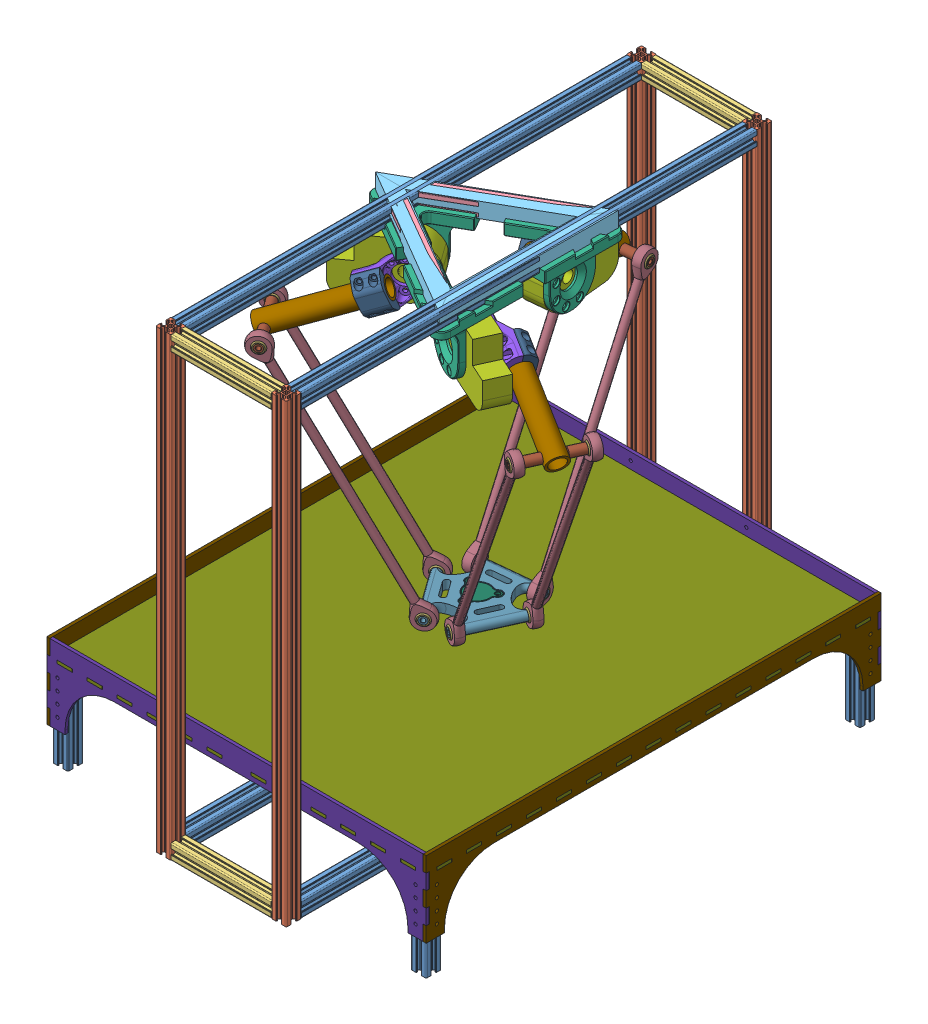
SolidWorks assembly delta-attached-dynamic-with-workspace, configuration Default. Lengths in mm.
Overall size (500 600 640).
80 component instances, 19 part files, 4 mates.
Components (placement in the parent):
- frame-1: frame [Default] at origin size (172.23 600 640)
  - alu-frame-length-1: alu-frame-length [End Finishing_Non-Machined End Finish Options_Type_Single_] at origin size (20 20 600)
  - alu-frame-height-1: alu-frame-height [End Finishing_Non-Machined End Finish Options_Type_Single_] at (0 -10 610) x (1 0 0) z (0 1 0) size (20 20 600)
  - alu-frame-height-2: alu-frame-height [End Finishing_Non-Machined End Finish Options_Type_Single_] at (0 -10 -10) x (1 0 0) z (0 1 0) size (20 20 600)
  - alu-frame-length-2: alu-frame-length [End Finishing_Non-Machined End Finish Options_Type_Single_] at (0 580 0) size (20 20 600)
  - alu-frame-width-1: alu-frame-width [End Finishing_Non-Machined End Finish Options_Type_Single_] at (10 0 610) x (0 0 -1) z (1 0 0) size (20 20 132.23)
  - alu-frame-width-2: alu-frame-width [End Finishing_Non-Machined End Finish Options_Type_Single_] at (10 0 -10) x (0 0 -1) z (1 0 0) size (20 20 132.23)
  - alu-frame-width-3: alu-frame-width [End Finishing_Non-Machined End Finish Options_Type_Single_] at (10 580 -10) x (0 0 -1) z (1 0 0) size (20 20 132.23)
  - alu-frame-width-4: alu-frame-width [End Finishing_Non-Machined End Finish Options_Type_Single_] at (10 580 610) x (0 0 -1) z (1 0 0) size (20 20 132.23)
  - alu-frame-height-3: alu-frame-height [End Finishing_Non-Machined End Finish Options_Type_Single_] at (152.23 -10 610) x (1 0 0) z (0 1 0) size (20 20 600)
  - alu-frame-height-4: alu-frame-height [End Finishing_Non-Machined End Finish Options_Type_Single_] at (152.23 -10 -10) x (1 0 0) z (0 1 0) size (20 20 600)
  - alu-frame-length-3: alu-frame-length [End Finishing_Non-Machined End Finish Options_Type_Single_] at (152.23 0 0) size (20 20 600)
  - alu-frame-length-4: alu-frame-length [End Finishing_Non-Machined End Finish Options_Type_Single_] at (152.23 580 0) size (20 20 600)
  - alu-frame-cross-strut-1: alu-frame-cross-strut [End Finishing_Non-Machined End Finish Options_Type_Single_] at (-10.4902 580 293.863) x (-0.5 0 -0.866025) z (0.866025 0 -0.5) size (20 20 164.23)
  - alu-frame-cross-strut-2: alu-frame-cross-strut [End Finishing_Non-Machined End Finish Options_Type_Single_] at (-10.4902 580 306.137) x (-0.5 0 0.866025) z (0.866025 0 0.5) size (20 20 164.23)
- delta-unattached-dynamic-1: delta-unattached-dynamic [Default] at (152.1394 570 300.5078) x (-0.006412 0 0.999979) z (-0.999979 0 -0.006412) size (388.36 442.87 421.7) (flexible)
  - base-1: base [Default] at origin size (276.1 104 273.55)
    - base^base-1: base^base [Default] at origin size (276.1 104 273.55) (virtual)
      - frame-triangle-1: frame-triangle [Default] at origin size (234.8 20 213.34)
        - frame-strut-triangle-1: frame-strut-triangle [Default] at origin size (234.8 20 20)
        - frame-strut-triangle-2: frame-strut-triangle [Default] at (50.04 0 86.6718) x (-0.5 0 0.866025) z (-0.866025 0 -0.5) size (234.8 20 20)
        - frame-strut-triangle-3: frame-strut-triangle [Default] at (-50.04 0 86.6718) x (-0.5 0 -0.866025) z (0.866025 0 -0.5) size (234.8 20 20)
      - base-mount-1: base-mount [Default] at (0 -47.5 143.3436) x (0.589337 0 0.807887) z (0 -1 0) size (108.14 103.78 86.5)
      - base-mount-2: base-mount [Default] at (74.0992 -47.5 15) x (0.404982 0 -0.914325) z (0 -1 0) size (108.14 103.78 86.5)
      - base-mount-3: base-mount [Default] at (-74.0992 -47.5 15) x (-0.994319 0 0.106438) z (0 -1 0) size (108.14 103.78 86.5)
      - Hebi-X5-1_draft-1: Hebi-X5-1_draft [Default] at (-95.9743 -47.5 17.3416) x (0 -1 0) z (-0.994319 0 0.106438) size (73 31.1 110)
      - Hebi-X5-1_draft-2: Hebi-X5-1_draft [Default] at (83.0088 -47.5 -5.1151) x (0 -1 0) z (0.404982 0 -0.914325) size (73 31.1 110)
      - Hebi-X5-1_draft-3: Hebi-X5-1_draft [Default] at (12.9654 -47.5 161.1172) x (0 -1 0) z (0.589337 0 0.807887) size (73 31.1 110)
  - proximal-link-1: proximal-link [Default] at (25.0038 -49.8947 147.2575) x (0.540088 -0.400189 0.740374) z (0.235846 0.916433 0.323308) size (174 92.2 48.61)
    - Proximal link^proximal-link-2: Proximal link^proximal-link [Default] at origin size (174 92.2 48.61) (virtual)
      - revolute-joint-1: revolute-joint [Default] at (-15.5275 13.2063 -4.1675) size (66.5 20.7 48.61)
      - proximal-link-1: proximal-link [Default] at (-3.0275 33.2063 -4.1675) x (0 0 -1) z (1 0 0) size (26 26 137.5)
      - joint-clamp-1: joint-clamp [Default] at (-3.0275 41.7563 -4.155) x (0 0 -1) z (1 0 0) size (48 17.3 30)
      - connection-tap-joint-1: connection-tap-joint [Default] at (124.4725 79.1063 -4.1675) x (0.500772 0 0.865579) z (0.865579 0 -0.500772) size (12 32.9 12)
      - connection-tap-joint-2: connection-tap-joint [Default] at (124.4725 -12.6937 -4.1675) x (0.550483 0 -0.834846) z (0.834846 0 0.550483) size (12 32.9 12)
      - distal-link-sphere-1: distal-link-sphere [Default] at (124.4725 72.3063 -4.1675) size (19 14 19)
      - distal-link-sphere-2: distal-link-sphere [Default] at (124.4725 -5.8937 -4.1675) size (19 14 19)
  - proximal-link-2: proximal-link [Default] at (64.9869 -49.8947 -8.6109) x (0.371139 -0.400189 -0.837917) z (0.162069 0.916433 -0.365903) size (174 92.2 48.61)
    - Proximal link^proximal-link-2: Proximal link^proximal-link [Default] at origin size (174 92.2 48.61) (virtual)
      - revolute-joint-1: revolute-joint [Default] at (-15.5275 13.2063 -4.1675) size (66.5 20.7 48.61)
      - proximal-link-1: proximal-link [Default] at (-3.0275 33.2063 -4.1675) x (0 0 -1) z (1 0 0) size (26 26 137.5)
      - joint-clamp-1: joint-clamp [Default] at (-3.0275 41.7563 -4.155) x (0 0 -1) z (1 0 0) size (48 17.3 30)
      - connection-tap-joint-1: connection-tap-joint [Default] at (124.4725 79.1063 -4.1675) x (0.500772 0 0.865579) z (0.865579 0 -0.500772) size (12 32.9 12)
      - connection-tap-joint-2: connection-tap-joint [Default] at (124.4725 -12.6937 -4.1675) x (0.550483 0 -0.834846) z (0.834846 0 0.550483) size (12 32.9 12)
      - distal-link-sphere-1: distal-link-sphere [Default] at (124.4725 72.3063 -4.1675) size (19 14 19)
      - distal-link-sphere-2: distal-link-sphere [Default] at (124.4725 -5.8937 -4.1675) size (19 14 19)
  - proximal-link-3: proximal-link [Default] at (-89.9907 -49.8947 34.697) x (-0.911227 -0.400189 0.097543) z (-0.397916 0.916433 0.042595) size (174 92.2 48.61)
    - Proximal link^proximal-link-2: Proximal link^proximal-link [Default] at origin size (174 92.2 48.61) (virtual)
      - revolute-joint-1: revolute-joint [Default] at (-15.5275 13.2063 -4.1675) size (66.5 20.7 48.61)
      - proximal-link-1: proximal-link [Default] at (-3.0275 33.2063 -4.1675) x (0 0 -1) z (1 0 0) size (26 26 137.5)
      - joint-clamp-1: joint-clamp [Default] at (-3.0275 41.7563 -4.155) x (0 0 -1) z (1 0 0) size (48 17.3 30)
      - connection-tap-joint-1: connection-tap-joint [Default] at (124.4725 79.1063 -4.1675) x (0.500772 0 0.865579) z (0.865579 0 -0.500772) size (12 32.9 12)
      - connection-tap-joint-2: connection-tap-joint [Default] at (124.4725 -12.6937 -4.1675) x (0.550483 0 -0.834846) z (0.834846 0 0.550483) size (12 32.9 12)
      - distal-link-sphere-1: distal-link-sphere [Default] at (124.4725 72.3063 -4.1675) size (19 14 19)
      - distal-link-sphere-2: distal-link-sphere [Default] at (124.4725 -5.8937 -4.1675) size (19 14 19)
  - distal-link-housing-1: distal-link-housing [Default] at (57.5455 -396.921 70.3212) x (0.804456 0.000771 -0.594012) z (0.277461 0.883719 0.376905) size (11 28.1 360.1)
  - distal-link-housing-2: distal-link-housing [Default] at (-5.6313 -396.921 116.4074) x (-0.80843 0.002791 0.588586) z (0.277461 0.883719 0.376905) size (11 28.1 360.1)
  - distal-link-housing-3: distal-link-housing [Default] at (-39.6327 -396.921 101.3471) x (-0.10843 0.001239 -0.994103) z (-0.465139 0.883719 0.051836) size (11 28.1 360.1)
  - distal-link-housing-4: distal-link-housing [Default] at (-47.9561 -396.921 23.5913) x (0.10843 -0.001239 0.994103) z (-0.465139 0.883719 0.051836) size (11 28.1 360.1)
  - distal-link-housing-6: distal-link-housing [Default] at (-17.9128 -396.921 1.6754) x (0.914947 0.001483 0.403571) z (0.187679 0.883719 -0.42874) size (11 28.1 360.1)
  - distal-link-housing-7: distal-link-housing [Default] at (53.5874 -396.921 33.345) x (0.914767 0.001719 0.403977) z (0.187679 0.883719 -0.42874) size (11 28.1 360.1)
  - flange-1: flange [Default] at (0 -402.875 57.7812) x (0.807887 0 -0.589337) z (0.589337 0 0.807887) size (140.68 41.57 122.81)
    - flange-star-1: flange-star [Default] at origin size (130.67 31.15 114.22)
    - calibration-pin-1: calibration-pin [Default] at (0 12 0) x (-1 0 0) z (0 0 1) size (44.16 32 40.5)
    - distal-link-sphere-1: distal-link-sphere [Default] at (39.1 5.9539 44.0446) x (0 -0.999016 0.044354) z (0 0.044354 0.999016) size (19 14 19)
    - distal-link-sphere-2: distal-link-sphere [Default] at (-39.1 5.9539 44.0446) x (0 -0.979762 0.200167) z (0 0.200167 0.979762) size (19 14 19)
    - distal-link-sphere-3: distal-link-sphere [Default] at (57.6937 5.9539 11.8393) x (0.173349 -0.979762 -0.100083) z (0.848499 0.200167 -0.489881) size (19 14 19)
    - distal-link-sphere-4: distal-link-sphere [Default] at (-18.5937 5.9539 -55.8839) x (-0.173349 -0.979762 -0.100083) z (-0.848499 0.200167 -0.489881) size (19 14 19)
    - distal-link-sphere-5: distal-link-sphere [Default] at (18.5937 5.9539 -55.8839) x (0.038412 -0.999016 -0.022177) z (0.865173 0.044354 -0.499508) size (19 14 19)
    - distal-link-sphere-6: distal-link-sphere [Default] at (-57.6937 5.9539 11.8393) x (-0.038412 -0.999016 -0.022177) z (-0.865173 0.044354 -0.499508) size (19 14 19)
- workspace-1: workspace [Default] at (76.115 119.3607 299.8125) x (0 0 1) z (-1 0 0) size (599.62 144 500)
  - basepanel-1: basepanel [Default] at origin size (599.62 4 500)
  - sidepanel-1: sidepanel [Default] at (299.8125 -76 -250) x (0 0 1) z (0 -1 0) size (500 4 100)
  - sidepanel-2: sidepanel [Default] at (-299.8125 -76 250) x (0 0 -1) z (0 -1 0) size (500 4 100)
  - rearpanel-1: rearpanel [Default] at (-0.0125 0 246) x (1 0 0) z (0 -1 0) size (599.6 4 100)
  - rearpanel-2: rearpanel [Default] at (-0.0125 0 -246) x (-1 0 0) z (0 -1 0) size (599.6 4 100)
  - alu-pillar-1: alu-pillar [End Finishing_Non-Machined End Finish Options_Type_Single_] at (-285.8125 0 -236) x (1 0 0) z (0 -1 0) size (20 20 120)
  - alu-pillar-2: alu-pillar [End Finishing_Non-Machined End Finish Options_Type_Single_] at (-285.8125 0 236) x (1 0 0) z (0 -1 0) size (20 20 120)
  - alu-pillar-3: alu-pillar [End Finishing_Non-Machined End Finish Options_Type_Single_] at (285.8125 0 -236) x (1 0 0) z (0 -1 0) size (20 20 120)
  - alu-pillar-5: alu-pillar [End Finishing_Non-Machined End Finish Options_Type_Single_] at (285.8125 0 236) x (1 0 0) z (0 -1 0) size (20 20 120)
Mates (geometry in assembly coordinates):
- Distance2: distance = 0.125 mm: plane of delta-unattached-dynamic-1/base-1/base^base-1/base-mount-3 through (142.105 570 226.3139) normal (1 0 0); plane of frame-1/alu-frame-length-4 through (142.23 576.25 600) normal (-1 0 0)
- Distance4: distance = 0.125 mm: plane of delta-unattached-dynamic-1/base-1/base^base-1/base-mount-2 through (134.4195 570 378.398) normal (-0.5 0 0.866025); plane of frame-1/alu-frame-cross-strut-2 through (167.7149 576.25 397.4768) normal (0.5 0 -0.866025)
- Coincident5: coincident: plane of frame-1/alu-frame-length-2 through (3.75 570 600) normal (0 -1 0); plane of delta-unattached-dynamic-1/base-1/base^base-1/base-mount-1 through (8.7987 570 299.5887) normal (0 1 0)
- Coincident6: coincident: plane of frame-1/alu-frame-height-4 through (155.98 590 0) normal (0 0 1); plane of workspace-1/sidepanel-2 through (-84.885 48.3607 0) normal (0 0 -1)
